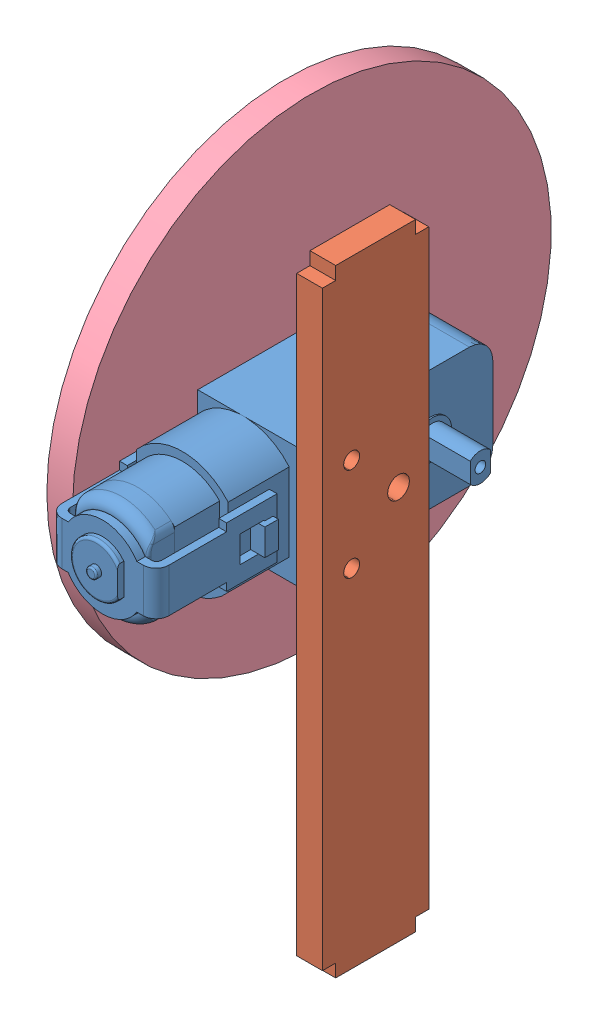
SolidWorks assembly Llanta - Izquierda, configuration Predeterminado. Lengths in mm.
Overall size (37.12 119 98.96).
4 component instances, 4 part files, 6 mates.
Components (placement in the parent):
- Motor - Amarillo DC 3-6 V-1: Motor - Amarillo DC 3-6 V [Predeterminado] at (-6.191 1.1029 58.84) size (37.12 22.62 70.64)
- Acrilico - Motor Columna-1: Acrilico - Motor Columna [Predeterminado] at (8.649 1.1029 67.28) x (-1 0 0) z (0 0 1) size (4.84 116 20)
- Acrilico - Llanta Acople-1: Acrilico - Llanta Acople [Predeterminado] at (-18.611 1.1029 52) size (2.44 10 10)
- Acrilico - Llanta-1: Acrilico - Llanta [Predeterminado] at (-23.451 1.1029 52) size (4.84 90 90)
Mates (geometry in assembly coordinates):
- Concéntrica1: concentric anti-aligned: circle of Motor - Amarillo DC 3-6 V-1; circle of Acrilico - Llanta Acople-1
- Coincidente3: coincident anti-aligned: plane of Motor - Amarillo DC 3-6 V-1 through (-16.171 1.1029 52) normal (-1 0 0); plane of Acrilico - Llanta Acople-1 through (-16.171 1.1029 52) normal (1 0 0)
- Concéntrica2: concentric anti-aligned: circle of Motor - Amarillo DC 3-6 V-1; circle of Acrilico - Llanta-1
- Coincidente9: coincident anti-aligned: plane of Acrilico - Llanta Acople-1 through (-18.611 1.1029 52) normal (-1 0 0); plane of Acrilico - Llanta-1 through (-18.611 1.1029 52) normal (1 0 0)
- Concéntrica4: concentric anti-aligned: circle of Motor - Amarillo DC 3-6 V-1; circle of Acrilico - Motor Columna-1
- Coincidente13: coincident anti-aligned: circle of Motor - Amarillo DC 3-6 V-1; circle of Acrilico - Motor Columna-1
